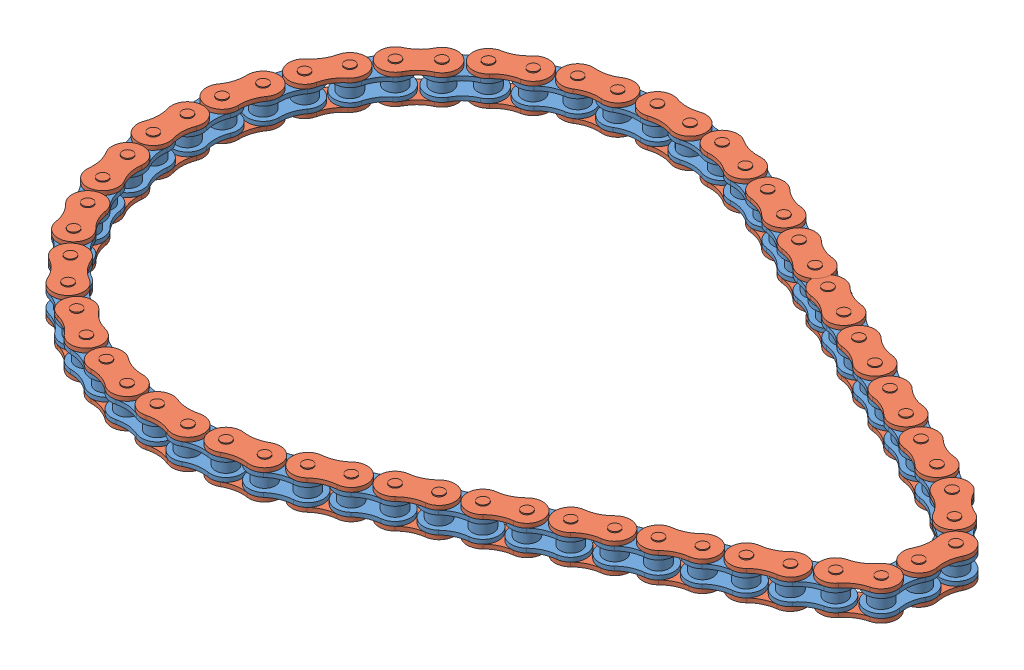
SolidWorks assembly PUTM-S-TR-GR-Chain, configuration Domyślna. Lengths in mm.
Overall size (384.91 15.35 264.99).
90 component instances, 2 part files, 0 mates.
Components (placement in the parent):
- PUTM-S-TR-GR-Chain-Links-1: PUTM-S-TR-GR-Chain-Links [Domyślna] at (123.0396 -38.14 -80.7699) x (-0.898235 0 -0.439516) z (0 1 0) size (46.98 15.68 15.35)
  - PUTM-S-TR-GR-Chain-Links-Inner-1: PUTM-S-TR-GR-Chain-Links-Inner [Domyślna] at (-11.2893 1.9082 25.79) size (30.96 15.09 10.35)
  - PUTM-S-TR-GR-Chain-Links-Outer-1: PUTM-S-TR-GR-Chain-Links-Outer [Domyślna] at (4.5857 1.9082 23.79) x (0.999816 0.019157 0) z (0.019157 -0.999816 0) size (30.96 15.35 15.09)
- PUTM-S-TR-GR-Chain-Links-2: PUTM-S-TR-GR-Chain-Links [Domyślna] at (151.6896 -38.14 -67.0897) x (-0.898235 0 -0.439516) z (0 1 0) size (46.98 15.68 15.35)
  - PUTM-S-TR-GR-Chain-Links-Inner-1: PUTM-S-TR-GR-Chain-Links-Inner [Domyślna] at (-11.2893 1.9082 25.79) size (30.96 15.09 10.35)
  - PUTM-S-TR-GR-Chain-Links-Outer-1: PUTM-S-TR-GR-Chain-Links-Outer [Domyślna] at (4.5857 1.9082 23.79) x (0.999816 0.019157 0) z (0.019157 -0.999816 0) size (30.96 15.35 15.09)
- PUTM-S-TR-GR-Chain-Links-3: PUTM-S-TR-GR-Chain-Links [Domyślna] at (180.3396 -38.14 -53.4095) x (-0.898235 0 -0.439516) z (0 1 0) size (46.98 15.68 15.35)
  - PUTM-S-TR-GR-Chain-Links-Inner-1: PUTM-S-TR-GR-Chain-Links-Inner [Domyślna] at (-11.2893 1.9082 25.79) size (30.96 15.09 10.35)
  - PUTM-S-TR-GR-Chain-Links-Outer-1: PUTM-S-TR-GR-Chain-Links-Outer [Domyślna] at (4.5857 1.9082 23.79) x (0.999816 0.019157 0) z (0.019157 -0.999816 0) size (30.96 15.35 15.09)
- PUTM-S-TR-GR-Chain-Links-4: PUTM-S-TR-GR-Chain-Links [Domyślna] at (208.9896 -38.14 -39.7293) x (-0.898235 0 -0.439516) z (0 1 0) size (46.98 15.68 15.35)
  - PUTM-S-TR-GR-Chain-Links-Inner-1: PUTM-S-TR-GR-Chain-Links-Inner [Domyślna] at (-11.2893 1.9082 25.79) size (30.96 15.09 10.35)
  - PUTM-S-TR-GR-Chain-Links-Outer-1: PUTM-S-TR-GR-Chain-Links-Outer [Domyślna] at (4.5857 1.9082 23.79) x (0.999816 0.019157 0) z (0.019157 -0.999816 0) size (30.96 15.35 15.09)
- PUTM-S-TR-GR-Chain-Links-5: PUTM-S-TR-GR-Chain-Links [Domyślna] at (234.7156 -38.14 -20.6575) x (-0.728787 0 -0.684741) z (0 1 0) size (46.98 15.68 15.35)
  - PUTM-S-TR-GR-Chain-Links-Inner-1: PUTM-S-TR-GR-Chain-Links-Inner [Domyślna] at (-11.2893 1.9082 25.79) size (30.96 15.09 10.35)
  - PUTM-S-TR-GR-Chain-Links-Outer-1: PUTM-S-TR-GR-Chain-Links-Outer [Domyślna] at (4.5857 1.9082 23.79) x (0.999816 0.019157 0) z (0.019157 -0.999816 0) size (30.96 15.35 15.09)
- PUTM-S-TR-GR-Chain-Links-6: PUTM-S-TR-GR-Chain-Links [Domyślna] at (240.697 -38.14 9.0191) x (0.152798 0 -0.988257) z (0 1 0) size (46.98 15.68 15.35)
  - PUTM-S-TR-GR-Chain-Links-Inner-1: PUTM-S-TR-GR-Chain-Links-Inner [Domyślna] at (-11.2893 1.9082 25.79) size (30.96 15.09 10.35)
  - PUTM-S-TR-GR-Chain-Links-Outer-1: PUTM-S-TR-GR-Chain-Links-Outer [Domyślna] at (4.5857 1.9082 23.79) x (0.999816 0.019157 0) z (0.019157 -0.999816 0) size (30.96 15.35 15.09)
- PUTM-S-TR-GR-Chain-Links-7: PUTM-S-TR-GR-Chain-Links [Domyślna] at (220.8702 -38.14 32.5513) x (0.849682 0 -0.527296) z (0 1 0) size (46.98 15.68 15.35)
  - PUTM-S-TR-GR-Chain-Links-Inner-1: PUTM-S-TR-GR-Chain-Links-Inner [Domyślna] at (-11.2893 1.9082 25.79) size (30.96 15.09 10.35)
  - PUTM-S-TR-GR-Chain-Links-Outer-1: PUTM-S-TR-GR-Chain-Links-Outer [Domyślna] at (4.5857 1.9082 23.79) x (0.999816 0.019157 0) z (0.019157 -0.999816 0) size (30.96 15.35 15.09)
- PUTM-S-TR-GR-Chain-Links-8: PUTM-S-TR-GR-Chain-Links [Domyślna] at (192.661 -38.14 47.5261) x (0.90649 0 -0.422228) z (0 1 0) size (46.98 15.68 15.35)
  - PUTM-S-TR-GR-Chain-Links-Inner-1: PUTM-S-TR-GR-Chain-Links-Inner [Domyślna] at (-11.2893 1.9082 25.79) size (30.96 15.09 10.35)
  - PUTM-S-TR-GR-Chain-Links-Outer-1: PUTM-S-TR-GR-Chain-Links-Outer [Domyślna] at (4.5857 1.9082 23.79) x (0.999816 0.019157 0) z (0.019157 -0.999816 0) size (30.96 15.35 15.09)
- PUTM-S-TR-GR-Chain-Links-9: PUTM-S-TR-GR-Chain-Links [Domyślna] at (164.011 -38.14 61.2063) x (0.90649 0 -0.422228) z (0 1 0) size (46.98 15.68 15.35)
  - PUTM-S-TR-GR-Chain-Links-Inner-1: PUTM-S-TR-GR-Chain-Links-Inner [Domyślna] at (-11.2893 1.9082 25.79) size (30.96 15.09 10.35)
  - PUTM-S-TR-GR-Chain-Links-Outer-1: PUTM-S-TR-GR-Chain-Links-Outer [Domyślna] at (4.5857 1.9082 23.79) x (0.999816 0.019157 0) z (0.019157 -0.999816 0) size (30.96 15.35 15.09)
- PUTM-S-TR-GR-Chain-Links-10: PUTM-S-TR-GR-Chain-Links [Domyślna] at (135.361 -38.14 74.8865) x (0.90649 0 -0.422228) z (0 1 0) size (46.98 15.68 15.35)
  - PUTM-S-TR-GR-Chain-Links-Inner-1: PUTM-S-TR-GR-Chain-Links-Inner [Domyślna] at (-11.2893 1.9082 25.79) size (30.96 15.09 10.35)
  - PUTM-S-TR-GR-Chain-Links-Outer-1: PUTM-S-TR-GR-Chain-Links-Outer [Domyślna] at (4.5857 1.9082 23.79) x (0.999816 0.019157 0) z (0.019157 -0.999816 0) size (30.96 15.35 15.09)
- PUTM-S-TR-GR-Chain-Links-11: PUTM-S-TR-GR-Chain-Links [Domyślna] at (106.711 -38.14 88.5667) x (0.90649 0 -0.422228) z (0 1 0) size (46.98 15.68 15.35)
  - PUTM-S-TR-GR-Chain-Links-Inner-1: PUTM-S-TR-GR-Chain-Links-Inner [Domyślna] at (-11.2893 1.9082 25.79) size (30.96 15.09 10.35)
  - PUTM-S-TR-GR-Chain-Links-Outer-1: PUTM-S-TR-GR-Chain-Links-Outer [Domyślna] at (4.5857 1.9082 23.79) x (0.999816 0.019157 0) z (0.019157 -0.999816 0) size (30.96 15.35 15.09)
- PUTM-S-TR-GR-Chain-Links-12: PUTM-S-TR-GR-Chain-Links [Domyślna] at (78.061 -38.14 102.2469) x (0.90649 0 -0.422228) z (0 1 0) size (46.98 15.68 15.35)
  - PUTM-S-TR-GR-Chain-Links-Inner-1: PUTM-S-TR-GR-Chain-Links-Inner [Domyślna] at (-11.2893 1.9082 25.79) size (30.96 15.09 10.35)
  - PUTM-S-TR-GR-Chain-Links-Outer-1: PUTM-S-TR-GR-Chain-Links-Outer [Domyślna] at (4.5857 1.9082 23.79) x (0.999816 0.019157 0) z (0.019157 -0.999816 0) size (30.96 15.35 15.09)
- PUTM-S-TR-GR-Chain-Links-13: PUTM-S-TR-GR-Chain-Links [Domyślna] at (49.0468 -38.14 115.2997) x (0.920809 0 -0.390013) z (0 1 0) size (46.98 15.68 15.35)
  - PUTM-S-TR-GR-Chain-Links-Inner-1: PUTM-S-TR-GR-Chain-Links-Inner [Domyślna] at (-11.2893 1.9082 25.79) size (30.96 15.09 10.35)
  - PUTM-S-TR-GR-Chain-Links-Outer-1: PUTM-S-TR-GR-Chain-Links-Outer [Domyślna] at (4.5857 1.9082 23.79) x (0.999816 0.019157 0) z (0.019157 -0.999816 0) size (30.96 15.35 15.09)
- PUTM-S-TR-GR-Chain-Links-14: PUTM-S-TR-GR-Chain-Links [Domyślna] at (18.1351 -38.14 123.6445) x (0.98509 0 -0.172041) z (0 1 0) size (46.98 15.68 15.35)
  - PUTM-S-TR-GR-Chain-Links-Inner-1: PUTM-S-TR-GR-Chain-Links-Inner [Domyślna] at (-11.2893 1.9082 25.79) size (30.96 15.09 10.35)
  - PUTM-S-TR-GR-Chain-Links-Outer-1: PUTM-S-TR-GR-Chain-Links-Outer [Domyślna] at (4.5857 1.9082 23.79) x (0.999816 0.019157 0) z (0.019157 -0.999816 0) size (30.96 15.35 15.09)
- PUTM-S-TR-GR-Chain-Links-15: PUTM-S-TR-GR-Chain-Links [Domyślna] at (-13.8854 -38.14 124.1936) x (0.996468 0 0.083975) z (0 1 0) size (46.98 15.68 15.35)
  - PUTM-S-TR-GR-Chain-Links-Inner-1: PUTM-S-TR-GR-Chain-Links-Inner [Domyślna] at (-11.2893 1.9082 25.79) size (30.96 15.09 10.35)
  - PUTM-S-TR-GR-Chain-Links-Outer-1: PUTM-S-TR-GR-Chain-Links-Outer [Domyślna] at (4.5857 1.9082 23.79) x (0.999816 0.019157 0) z (0.019157 -0.999816 0) size (30.96 15.35 15.09)
- PUTM-S-TR-GR-Chain-Links-16: PUTM-S-TR-GR-Chain-Links [Domyślna] at (-44.9941 -38.14 116.5863) x (0.942404 0 0.334476) z (0 1 0) size (46.98 15.68 15.35)
  - PUTM-S-TR-GR-Chain-Links-Inner-1: PUTM-S-TR-GR-Chain-Links-Inner [Domyślna] at (-11.2893 1.9082 25.79) size (30.96 15.09 10.35)
  - PUTM-S-TR-GR-Chain-Links-Outer-1: PUTM-S-TR-GR-Chain-Links-Outer [Domyślna] at (4.5857 1.9082 23.79) x (0.999816 0.019157 0) z (0.019157 -0.999816 0) size (30.96 15.35 15.09)
- PUTM-S-TR-GR-Chain-Links-17: PUTM-S-TR-GR-Chain-Links [Domyślna] at (-73.1478 -38.14 101.3225) x (0.826449 0 0.563012) z (0 1 0) size (46.98 15.68 15.35)
  - PUTM-S-TR-GR-Chain-Links-Inner-1: PUTM-S-TR-GR-Chain-Links-Inner [Domyślna] at (-11.2893 1.9082 25.79) size (30.96 15.09 10.35)
  - PUTM-S-TR-GR-Chain-Links-Outer-1: PUTM-S-TR-GR-Chain-Links-Outer [Domyślna] at (4.5857 1.9082 23.79) x (0.999816 0.019157 0) z (0.019157 -0.999816 0) size (30.96 15.35 15.09)
- PUTM-S-TR-GR-Chain-Links-18: PUTM-S-TR-GR-Chain-Links [Domyślna] at (-96.4977 -38.14 79.4043) x (0.656218 0 0.754571) z (0 1 0) size (46.98 15.68 15.35)
  - PUTM-S-TR-GR-Chain-Links-Inner-1: PUTM-S-TR-GR-Chain-Links-Inner [Domyślna] at (-11.2893 1.9082 25.79) size (30.96 15.09 10.35)
  - PUTM-S-TR-GR-Chain-Links-Outer-1: PUTM-S-TR-GR-Chain-Links-Outer [Domyślna] at (4.5857 1.9082 23.79) x (0.999816 0.019157 0) z (0.019157 -0.999816 0) size (30.96 15.35 15.09)
- PUTM-S-TR-GR-Chain-Links-19: PUTM-S-TR-GR-Chain-Links [Domyślna] at (-113.5101 -38.14 52.2714) x (0.44289 0 0.896576) z (0 1 0) size (46.98 15.68 15.35)
  - PUTM-S-TR-GR-Chain-Links-Inner-1: PUTM-S-TR-GR-Chain-Links-Inner [Domyślna] at (-11.2893 1.9082 25.79) size (30.96 15.09 10.35)
  - PUTM-S-TR-GR-Chain-Links-Outer-1: PUTM-S-TR-GR-Chain-Links-Outer [Domyślna] at (4.5857 1.9082 23.79) x (0.999816 0.019157 0) z (0.019157 -0.999816 0) size (30.96 15.35 15.09)
- PUTM-S-TR-GR-Chain-Links-20: PUTM-S-TR-GR-Chain-Links [Domyślna] at (-123.0679 -38.14 21.7056) x (0.200476 0 0.979699) z (0 1 0) size (46.98 15.68 15.35)
  - PUTM-S-TR-GR-Chain-Links-Inner-1: PUTM-S-TR-GR-Chain-Links-Inner [Domyślna] at (-11.2893 1.9082 25.79) size (30.96 15.09 10.35)
  - PUTM-S-TR-GR-Chain-Links-Outer-1: PUTM-S-TR-GR-Chain-Links-Outer [Domyślna] at (4.5857 1.9082 23.79) x (0.999816 0.019157 0) z (0.019157 -0.999816 0) size (30.96 15.35 15.09)
- PUTM-S-TR-GR-Chain-Links-21: PUTM-S-TR-GR-Chain-Links [Domyślna] at (-124.5434 -38.14 -10.2857) x (-0.055103 0 0.998481) z (0 1 0) size (46.98 15.68 15.35)
  - PUTM-S-TR-GR-Chain-Links-Inner-1: PUTM-S-TR-GR-Chain-Links-Inner [Domyślna] at (-11.2893 1.9082 25.79) size (30.96 15.09 10.35)
  - PUTM-S-TR-GR-Chain-Links-Outer-1: PUTM-S-TR-GR-Chain-Links-Outer [Domyślna] at (4.5857 1.9082 23.79) x (0.999816 0.019157 0) z (0.019157 -0.999816 0) size (30.96 15.35 15.09)
- PUTM-S-TR-GR-Chain-Links-22: PUTM-S-TR-GR-Chain-Links [Domyślna] at (-117.8396 -38.14 -41.6014) x (-0.307065 0 0.951689) z (0 1 0) size (46.98 15.68 15.35)
  - PUTM-S-TR-GR-Chain-Links-Inner-1: PUTM-S-TR-GR-Chain-Links-Inner [Domyślna] at (-11.2893 1.9082 25.79) size (30.96 15.09 10.35)
  - PUTM-S-TR-GR-Chain-Links-Outer-1: PUTM-S-TR-GR-Chain-Links-Outer [Domyślna] at (4.5857 1.9082 23.79) x (0.999816 0.019157 0) z (0.019157 -0.999816 0) size (30.96 15.35 15.09)
- PUTM-S-TR-GR-Chain-Links-23: PUTM-S-TR-GR-Chain-Links [Domyślna] at (-103.3968 -38.14 -70.1851) x (-0.53886 0 0.842396) z (0 1 0) size (46.98 15.68 15.35)
  - PUTM-S-TR-GR-Chain-Links-Inner-1: PUTM-S-TR-GR-Chain-Links-Inner [Domyślna] at (-11.2893 1.9082 25.79) size (30.96 15.09 10.35)
  - PUTM-S-TR-GR-Chain-Links-Outer-1: PUTM-S-TR-GR-Chain-Links-Outer [Domyślna] at (4.5857 1.9082 23.79) x (0.999816 0.019157 0) z (0.019157 -0.999816 0) size (30.96 15.35 15.09)
- PUTM-S-TR-GR-Chain-Links-24: PUTM-S-TR-GR-Chain-Links [Domyślna] at (-82.1636 -38.14 -94.1594) x (-0.735265 0 0.677779) z (0 1 0) size (46.98 15.68 15.35)
  - PUTM-S-TR-GR-Chain-Links-Inner-1: PUTM-S-TR-GR-Chain-Links-Inner [Domyślna] at (-11.2893 1.9082 25.79) size (30.96 15.09 10.35)
  - PUTM-S-TR-GR-Chain-Links-Outer-1: PUTM-S-TR-GR-Chain-Links-Outer [Domyślna] at (4.5857 1.9082 23.79) x (0.999816 0.019157 0) z (0.019157 -0.999816 0) size (30.96 15.35 15.09)
- PUTM-S-TR-GR-Chain-Links-25: PUTM-S-TR-GR-Chain-Links [Domyślna] at (-55.5343 -38.14 -111.9499) x (-0.883384 0 0.46865) z (0 1 0) size (46.98 15.68 15.35)
  - PUTM-S-TR-GR-Chain-Links-Inner-1: PUTM-S-TR-GR-Chain-Links-Inner [Domyślna] at (-11.2893 1.9082 25.79) size (30.96 15.09 10.35)
  - PUTM-S-TR-GR-Chain-Links-Outer-1: PUTM-S-TR-GR-Chain-Links-Outer [Domyślna] at (4.5857 1.9082 23.79) x (0.999816 0.019157 0) z (0.019157 -0.999816 0) size (30.96 15.35 15.09)
- PUTM-S-TR-GR-Chain-Links-26: PUTM-S-TR-GR-Chain-Links [Domyślna] at (-25.2579 -38.14 -122.3882) x (-0.973487 0 0.228743) z (0 1 0) size (46.98 15.68 15.35)
  - PUTM-S-TR-GR-Chain-Links-Inner-1: PUTM-S-TR-GR-Chain-Links-Inner [Domyślna] at (-11.2893 1.9082 25.79) size (30.96 15.09 10.35)
  - PUTM-S-TR-GR-Chain-Links-Outer-1: PUTM-S-TR-GR-Chain-Links-Outer [Domyślna] at (4.5857 1.9082 23.79) x (0.999816 0.019157 0) z (0.019157 -0.999816 0) size (30.96 15.35 15.09)
- PUTM-S-TR-GR-Chain-Links-27: PUTM-S-TR-GR-Chain-Links [Domyślna] at (6.6773 -38.14 -124.7889) x (-0.999657 0 -0.026186) z (0 1 0) size (46.98 15.68 15.35)
  - PUTM-S-TR-GR-Chain-Links-Inner-1: PUTM-S-TR-GR-Chain-Links-Inner [Domyślna] at (-11.2893 1.9082 25.79) size (30.96 15.09 10.35)
  - PUTM-S-TR-GR-Chain-Links-Outer-1: PUTM-S-TR-GR-Chain-Links-Outer [Domyślna] at (4.5857 1.9082 23.79) x (0.999816 0.019157 0) z (0.019157 -0.999816 0) size (30.96 15.35 15.09)
- PUTM-S-TR-GR-Chain-Links-28: PUTM-S-TR-GR-Chain-Links [Domyślna] at (38.1739 -38.14 -118.9941) x (-0.960176 0 -0.279396) z (0 1 0) size (46.98 15.68 15.35)
  - PUTM-S-TR-GR-Chain-Links-Inner-1: PUTM-S-TR-GR-Chain-Links-Inner [Domyślna] at (-11.2893 1.9082 25.79) size (30.96 15.09 10.35)
  - PUTM-S-TR-GR-Chain-Links-Outer-1: PUTM-S-TR-GR-Chain-Links-Outer [Domyślna] at (4.5857 1.9082 23.79) x (0.999816 0.019157 0) z (0.019157 -0.999816 0) size (30.96 15.35 15.09)
- PUTM-S-TR-GR-Chain-Links-29: PUTM-S-TR-GR-Chain-Links [Domyślna] at (67.8544 -38.14 -107.0745) x (-0.899844 0 -0.436212) z (0 1 0) size (46.98 15.68 15.35)
  - PUTM-S-TR-GR-Chain-Links-Inner-1: PUTM-S-TR-GR-Chain-Links-Inner [Domyślna] at (-11.2893 1.9082 25.79) size (30.96 15.09 10.35)
  - PUTM-S-TR-GR-Chain-Links-Outer-1: PUTM-S-TR-GR-Chain-Links-Outer [Domyślna] at (4.5857 1.9082 23.79) x (0.999816 0.019157 0) z (0.019157 -0.999816 0) size (30.96 15.35 15.09)
- PUTM-S-TR-GR-Chain-Links-30: PUTM-S-TR-GR-Chain-Links [Domyślna] at (96.5288 -38.14 -93.4286) x (-0.898235 0 -0.439516) z (0 1 0) size (46.98 15.68 15.35)
  - PUTM-S-TR-GR-Chain-Links-Inner-1: PUTM-S-TR-GR-Chain-Links-Inner [Domyślna] at (-11.2893 1.9082 25.79) size (30.96 15.09 10.35)
  - PUTM-S-TR-GR-Chain-Links-Outer-1: PUTM-S-TR-GR-Chain-Links-Outer [Domyślna] at (4.5857 1.9082 23.79) x (0.999816 0.019157 0) z (0.019157 -0.999816 0) size (30.96 15.35 15.09)
